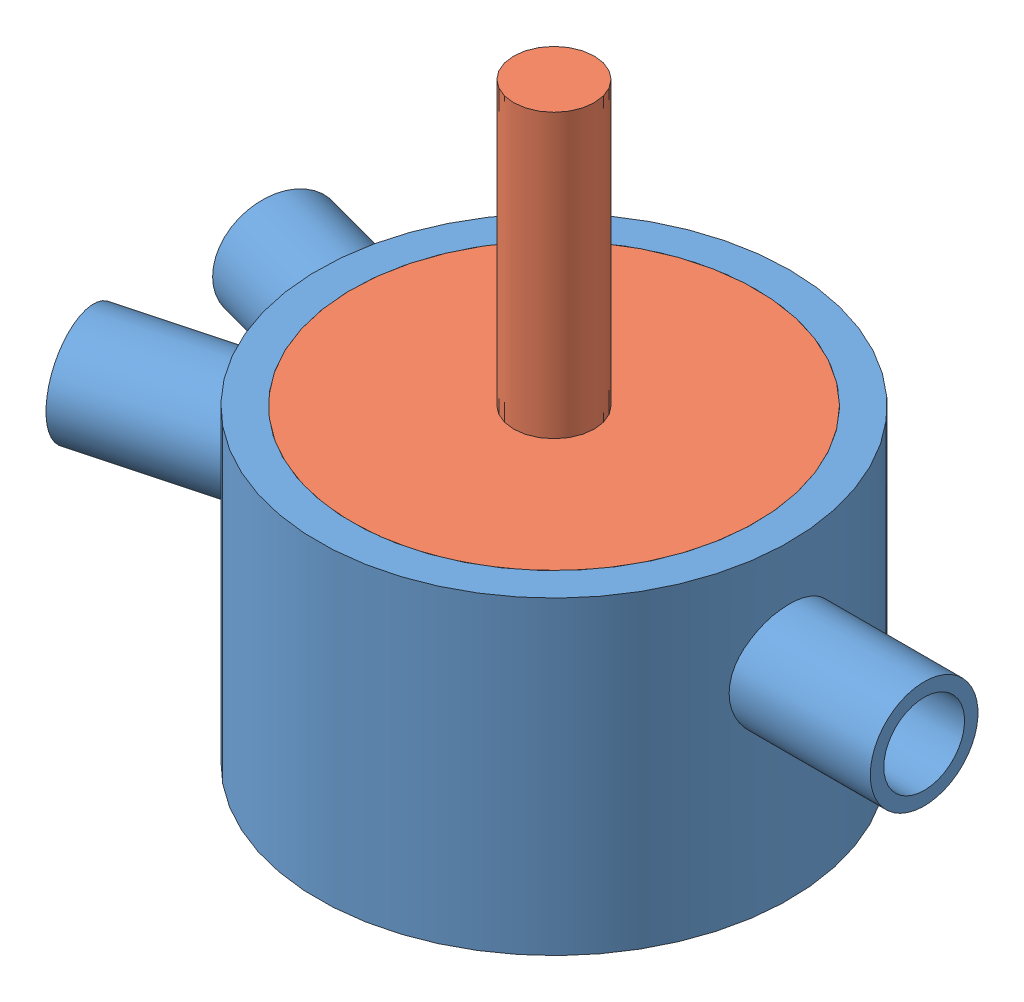
SolidWorks assembly Montagem1, configuration Valor predeterminado. Lengths in mm.
Overall size (56.48 44 36.82).
2 component instances, 2 part files, 2 mates.
Components (placement in the parent):
- Sede_Inferior_nova-2: Sede_Inferior_nova [Valor predeterminado<Como usinado>] at origin size (56.48 23 35)
- Desviador-1: Desviador [Valor predeterminado] x (-0.965 0 0.262249) z (-0.262249 0 -0.965) size (30 41.5 30)
Mates (geometry in assembly coordinates):
- Coincidente3: coordinate: point of Sede_Inferior_nova-2; point of assembly
- Articulação1: hinge anti-aligned: cylinder of Desviador-1 through (0 0 0) axis (0 -1 0) radius 3; cylinder of Sede_Inferior_nova-2 through (0 0 0) axis (0 -1 0) radius 3.25; plane of Sede_Inferior_nova-2 through (3.25 -12.5 0) normal (0 1 0); plane of Desviador-1 through (-2.895 -12.5 0.7867) normal (0 -1 0)
